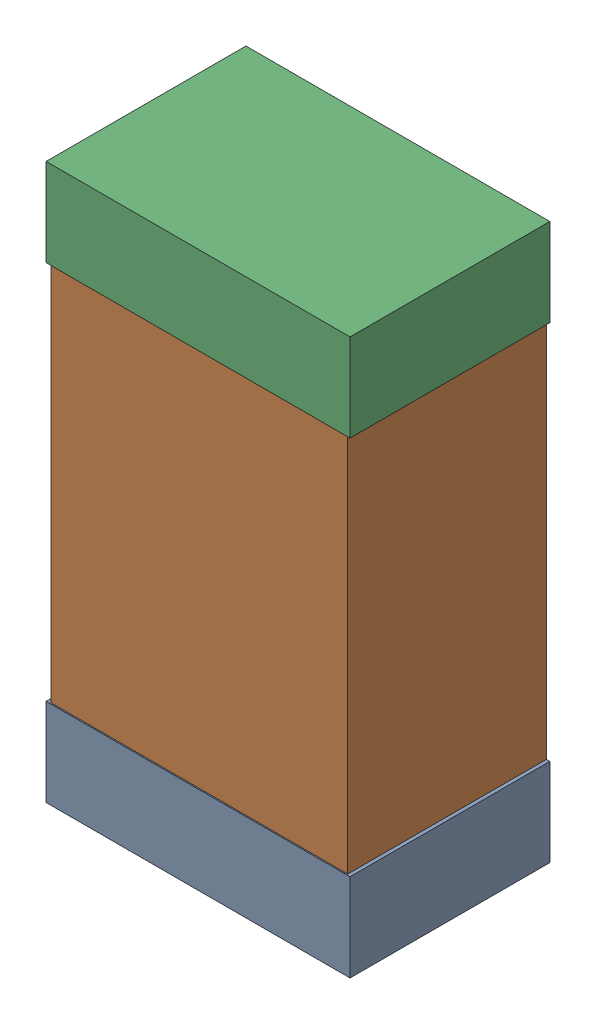
SolidWorks assembly 22pFKanaloa_v2.0.0_Power, configuration Default. Lengths in mm.
Overall size (1.3 2.38 0.85).
6 component instances, 2 part files, 0 mates.
Components (placement in the parent):
- 330415056-1: 330415056 [Default] at (146.7708 88.0504 0) size (1.3 0.38 0.85)
  - Extruded_2-1: Extruded_2 [Default] at origin size (1.3 0.38 0.85)
- 334787376-1: 334787376 [Default] at (146.7708 89.0504 0) size (1.27 2.2 0.85)
  - Extruded_16-1: Extruded_16 [Default] at origin size (1.27 2.2 0.85)
- 330415056-2: 330415056 [Default] at (146.7708 90.0504 0) size (1.3 0.38 0.85)
  - Extruded_2-1: Extruded_2 [Default] at origin size (1.3 0.38 0.85)
